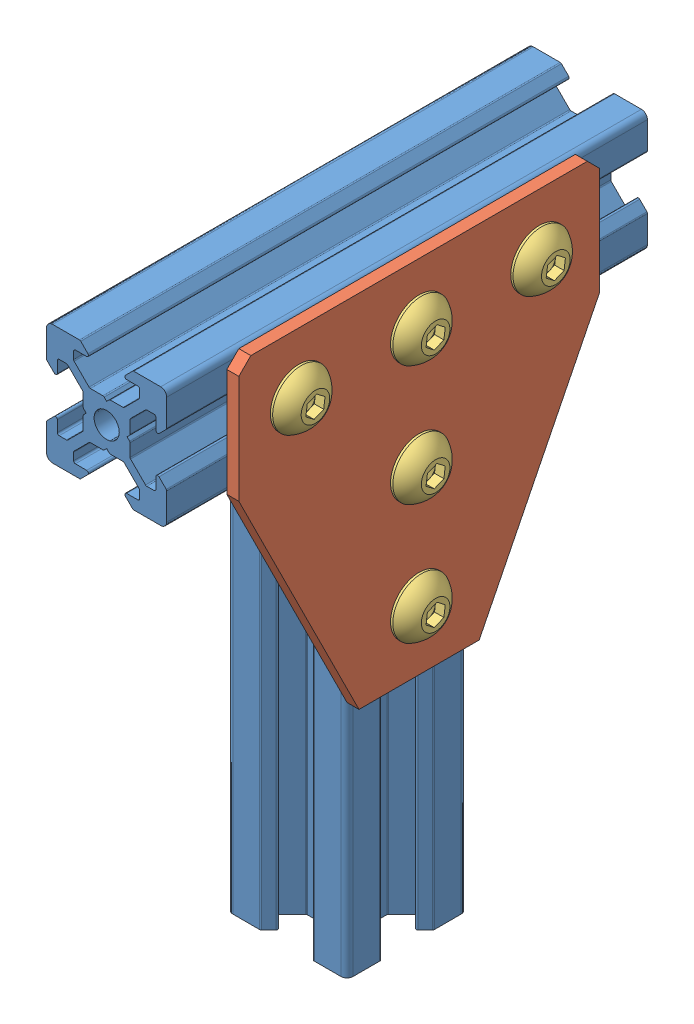
SolidWorks assembly Т-пластина 20 серия 3х3 5отв 60х60х2 усил, configuration По умолчанию. Lengths in mm.
Overall size (24.75 100 80).
8 component instances, 3 part files, 16 mates.
Components (placement in the parent):
- 2020100-1: 2020100 [По умолчанию] at origin size (20 20 80)
- 2020100-2: 2020100 [По умолчанию] at (0 -90 40) x (1 0 0) z (0 1 0) size (20 20 80)
- Т-пластина 20 серия 3х3 5отв 60х60х2 усил.-1: Т-пластина 20 серия 3х3 5отв 60х60х2 усил. [По умолчанию] at (10 -50 40) x (0 0 -1) z (0 -1 0) size (60 2 60)
- socket button head screw_iso-5: socket button head screw_iso [ISO 7380 - M5 x 10 - 10N] at (14.75 0 60) x (-1 0 0) z (0 0.924225 0.381849) size (12.75 9.5 9.5)
- socket button head screw_iso-6: socket button head screw_iso [ISO 7380 - M5 x 10 - 10N] at (14.75 0 20) x (-1 0 0) z (0 0.924225 0.381849) size (12.75 9.5 9.5)
- socket button head screw_iso-7: socket button head screw_iso [ISO 7380 - M5 x 10 - 10N] at (14.75 -20 40) x (-1 0 0) z (0 0.924225 0.381849) size (12.75 9.5 9.5)
- socket button head screw_iso-8: socket button head screw_iso [ISO 7380 - M5 x 10 - 10N] at (14.75 -40 40) x (-1 0 0) z (0 0.924225 0.381849) size (12.75 9.5 9.5)
- socket button head screw_iso-9: socket button head screw_iso [ISO 7380 - M5 x 10 - 10N] at (14.75 0 40) x (-1 0 0) z (0 0.924225 0.381849) size (12.75 9.5 9.5)
Mates (geometry in assembly coordinates):
- Совпадение1: coincident aligned: plane of 2020100-1 through (10 -10 80) normal (1 0 0); plane of 2020100-2 through (10 -10 30) normal (1 0 0)
- Совпадение2: coincident anti-aligned: plane of 2020100-1 through (10 -10 80) normal (0 -1 0); plane of 2020100-2 through (0 -10 40) normal (0 1 0)
- Расстояние1: distance = 30 mm aligned: plane of 2020100-2 through (-10 -10 50) normal (0 0 1); plane of 2020100-1 through (0 0 80) normal (0 0 1)
- Совпадение3: coincident anti-aligned: plane of 2020100-1 through (10 -10 80) normal (1 0 0); plane of Т-пластина 20 серия 2х3 4отв 40х60х2 усил.-1 through (10 -50 40) normal (-1 0 0)
- Совпадение4: coincident aligned: plane of 2020100-1 through (10 10 80) normal (0 1 0); plane of Т-пластина 20 серия 2х3 4отв 40х60х2 усил.-1 through (12 10 70) normal (0 1 0)
- Совпадение5: coincident: plane of 2020100-2 through (10 -10 50) normal (0 0 1); line of Т-пластина 20 серия 2х3 4отв 40х60х2 усил.-1 through (12 -50 50) axis (-1 0 0)
- Концентричный1: concentric aligned: cylinder of Т-пластина 20 серия 2х3 4отв 40х60х2 усил.-1 through (12 0 60) axis (1 0 0) radius 2.75; cylinder of socket button head screw_iso-5 through (14.75 0 60) axis (1 0 0) radius 4.75
- Совпадение6: coincident anti-aligned: plane of Т-пластина 20 серия 2х3 4отв 40х60х2 усил.-1 through (12 -50 40) normal (1 0 0); plane of socket button head screw_iso-5 through (12 -0.9546 62.3106) normal (-1 0 0)
- Концентричный2: concentric aligned: cylinder of Т-пластина 20 серия 2х3 4отв 40х60х2 усил.-1 through (12 0 20) axis (1 0 0) radius 2.75; cylinder of socket button head screw_iso-6 through (14.75 0 20) axis (1 0 0) radius 4.75
- Совпадение7: coincident anti-aligned: plane of Т-пластина 20 серия 2х3 4отв 40х60х2 усил.-1 through (12 -50 40) normal (1 0 0); plane of socket button head screw_iso-6 through (12 -0.9546 22.3106) normal (-1 0 0)
- Концентричный3: concentric aligned: cylinder of Т-пластина 20 серия 2х3 4отв 40х60х2 усил.-1 through (12 -20 40) axis (1 0 0) radius 2.75; cylinder of socket button head screw_iso-7 through (14.75 -20 40) axis (1 0 0) radius 4.75
- Совпадение8: coincident anti-aligned: plane of Т-пластина 20 серия 2х3 4отв 40х60х2 усил.-1 through (12 -50 40) normal (1 0 0); plane of socket button head screw_iso-7 through (12 -20.9546 42.3106) normal (-1 0 0)
- Концентричный4: concentric aligned: cylinder of Т-пластина 20 серия 2х3 4отв 40х60х2 усил.-1 through (12 -40 40) axis (1 0 0) radius 2.75; cylinder of socket button head screw_iso-8 through (14.75 -40 40) axis (1 0 0) radius 4.75
- Совпадение9: coincident anti-aligned: plane of Т-пластина 20 серия 2х3 4отв 40х60х2 усил.-1 through (12 -50 40) normal (1 0 0); plane of socket button head screw_iso-8 through (12 -40.9546 42.3106) normal (-1 0 0)
- Концентричный5: concentric aligned: cylinder of Т-пластина 20 серия 3х3 5отв 60х60х2 усил.-1 through (12 0 40) axis (1 0 0) radius 2.75; cylinder of socket button head screw_iso-9 through (14.75 0 40) axis (1 0 0) radius 4.75
- Совпадение10: coincident anti-aligned: plane of Т-пластина 20 серия 3х3 5отв 60х60х2 усил.-1 through (12 -50 40) normal (1 0 0); plane of socket button head screw_iso-9 through (12 -0.9546 42.3106) normal (-1 0 0)
